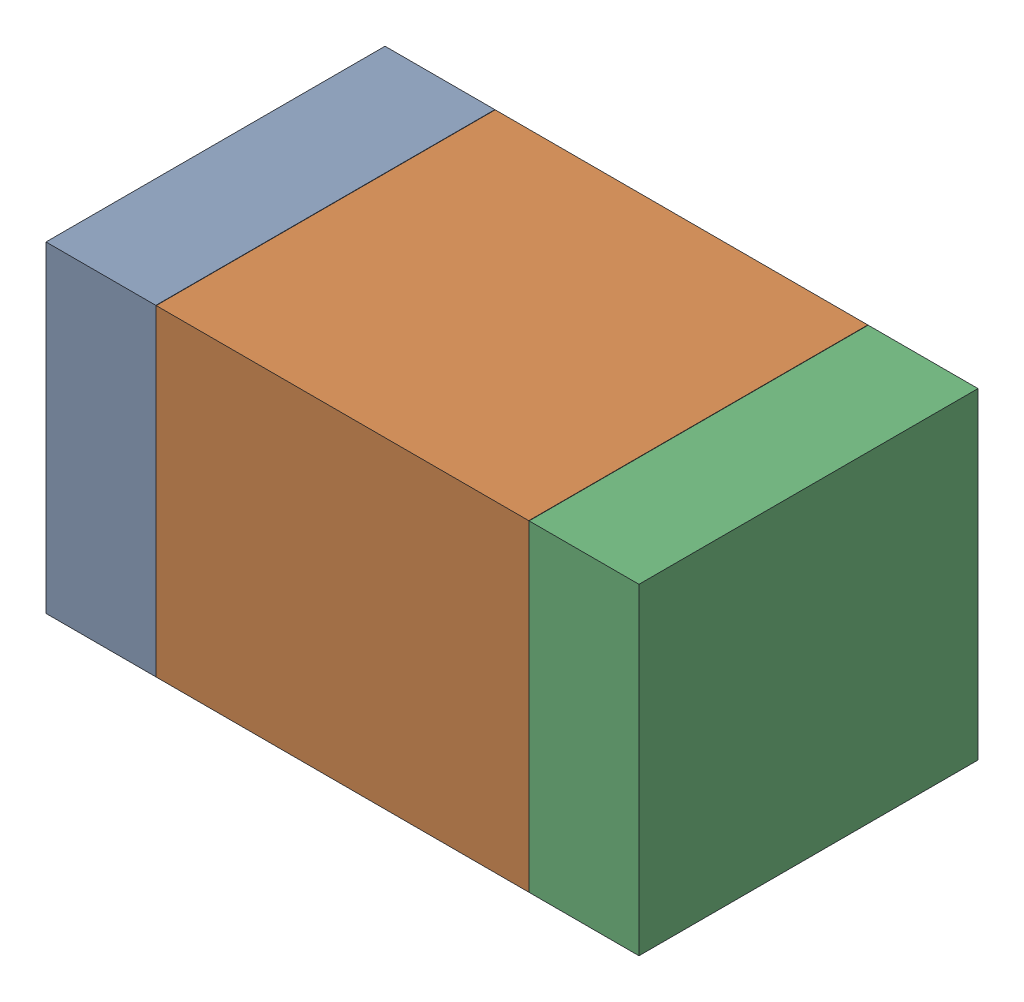
SolidWorks assembly R29, configuration Default. Lengths in mm.
Overall size (1.75 0.95 1).
6 component instances, 2 part files, 0 mates.
Components (placement in the parent):
- 6575498272-1: 6575498272 [Default] at (49.0715 5.207 0) size (0.32 0.95 1)
  - Extruded_8-1: Extruded_8 [Default] at origin size (0.32 0.95 1)
- 6575498112-1: 6575498112 [Default] at (49.784 5.207 0) size (1.1 0.95 1)
  - Extruded_9-1: Extruded_9 [Default] at origin size (1.1 0.95 1)
- 6575498272-2: 6575498272 [Default] at (50.4965 5.207 0) size (0.32 0.95 1)
  - Extruded_8-1: Extruded_8 [Default] at origin size (0.32 0.95 1)
